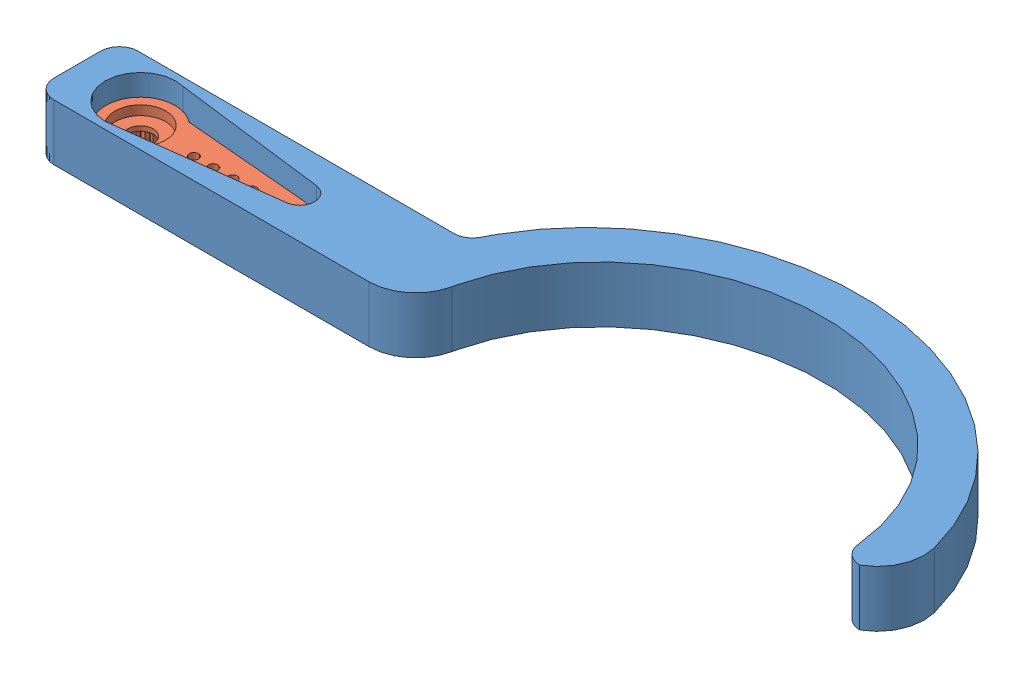
SolidWorks assembly LeftClaw, configuration 默认. Lengths in mm.
Overall size (90.57 6.35 25).
2 component instances, 2 part files, 3 mates.
Components (placement in the parent):
- clawL1-1: clawL1 [默认] at (-37.7512 -6.0128 98.569) size (90.57 6 25)
- MG90_Arm-1: MG90_Arm [默认] at (-37.7512 -2.2628 98.569) x (0 0 -1) z (-1 0 0) size (7.4 4.1 20.9)
Mates (geometry in assembly coordinates):
- 同心1: concentric aligned: cylinder of clawL1-1 through (-37.7512 -0.0128 98.569) axis (0 -1 0) radius 3.75; cylinder of MG90_Arm-1 through (-37.7512 -2.2628 98.569) axis (0 -1 0) radius 3.7
- 重合3: coincident anti-aligned: plane of clawL1-1 through (-37.7512 -4.0128 98.569) normal (0 1 0); plane of MG90_Arm-1 through (-31.0012 -4.0128 98.569) normal (0 -1 0)
- 平行5: parallel aligned: line of clawL1-1 through (-37.7512 -6.0128 98.569) axis (1 0 0); line of MG90_Arm-1 through (-37.7512 -2.2628 98.569) axis (1 0 0)
